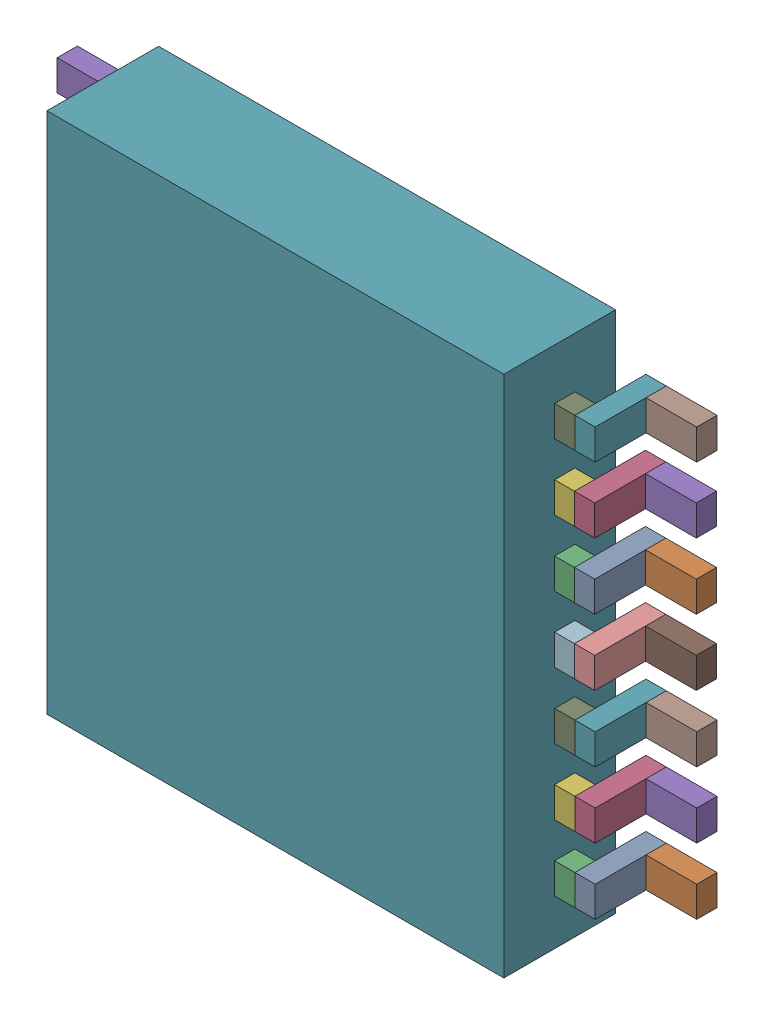
SolidWorks assembly U10, configuration Default. Lengths in mm.
Overall size (6.3 5.15 1.2).
86 component instances, 4 part files, 0 mates.
Components (placement in the parent):
- 836750064-1: 836750064 [Default] at (113.1 40.4 0) size (0.2 0.3 0.7)
  - Extruded_24-1: Extruded_24 [Default] at origin size (0.2 0.3 0.7)
- 836751344-1: 836751344 [Default] at (113.45 40.4 0) size (0.5 0.3 0.2)
  - Extruded_25-1: Extruded_25 [Default] at origin size (0.5 0.3 0.2)
- 836749808-1: 836749808 [Default] at (112.9 40.4 0.5) size (0.2 0.3 0.2)
  - Extruded_26-1: Extruded_26 [Default] at origin size (0.2 0.3 0.2)
- 836750064-2: 836750064 [Default] at (113.1 41.05 0) size (0.2 0.3 0.7)
  - Extruded_24-1: Extruded_24 [Default] at origin size (0.2 0.3 0.7)
- 836751344-2: 836751344 [Default] at (113.45 41.05 0) size (0.5 0.3 0.2)
  - Extruded_25-1: Extruded_25 [Default] at origin size (0.5 0.3 0.2)
- 836749808-2: 836749808 [Default] at (112.9 41.05 0.5) size (0.2 0.3 0.2)
  - Extruded_26-1: Extruded_26 [Default] at origin size (0.2 0.3 0.2)
- 836750064-3: 836750064 [Default] at (113.1 41.7 0) size (0.2 0.3 0.7)
  - Extruded_24-1: Extruded_24 [Default] at origin size (0.2 0.3 0.7)
- 836751344-3: 836751344 [Default] at (113.45 41.7 0) size (0.5 0.3 0.2)
  - Extruded_25-1: Extruded_25 [Default] at origin size (0.5 0.3 0.2)
- 836749808-3: 836749808 [Default] at (112.9 41.7 0.5) size (0.2 0.3 0.2)
  - Extruded_26-1: Extruded_26 [Default] at origin size (0.2 0.3 0.2)
- 836750064-4: 836750064 [Default] at (113.0954 42.35 0) size (0.2 0.3 0.7)
  - Extruded_24-1: Extruded_24 [Default] at origin size (0.2 0.3 0.7)
- 836751344-4: 836751344 [Default] at (113.4454 42.35 0) size (0.5 0.3 0.2)
  - Extruded_25-1: Extruded_25 [Default] at origin size (0.5 0.3 0.2)
- 836749808-4: 836749808 [Default] at (112.8954 42.35 0.5) size (0.2 0.3 0.2)
  - Extruded_26-1: Extruded_26 [Default] at origin size (0.2 0.3 0.2)
- 836750064-5: 836750064 [Default] at (113.0954 43 0) size (0.2 0.3 0.7)
  - Extruded_24-1: Extruded_24 [Default] at origin size (0.2 0.3 0.7)
- 836751344-5: 836751344 [Default] at (113.4454 43 0) size (0.5 0.3 0.2)
  - Extruded_25-1: Extruded_25 [Default] at origin size (0.5 0.3 0.2)
- 836749808-5: 836749808 [Default] at (112.8954 43 0.5) size (0.2 0.3 0.2)
  - Extruded_26-1: Extruded_26 [Default] at origin size (0.2 0.3 0.2)
- 836750064-6: 836750064 [Default] at (113.0954 43.65 0) size (0.2 0.3 0.7)
  - Extruded_24-1: Extruded_24 [Default] at origin size (0.2 0.3 0.7)
- 836751344-6: 836751344 [Default] at (113.4454 43.65 0) size (0.5 0.3 0.2)
  - Extruded_25-1: Extruded_25 [Default] at origin size (0.5 0.3 0.2)
- 836749808-6: 836749808 [Default] at (112.8954 43.65 0.5) size (0.2 0.3 0.2)
  - Extruded_26-1: Extruded_26 [Default] at origin size (0.2 0.3 0.2)
- 836750064-7: 836750064 [Default] at (113.1 44.3 0) size (0.2 0.3 0.7)
  - Extruded_24-1: Extruded_24 [Default] at origin size (0.2 0.3 0.7)
- 836751344-7: 836751344 [Default] at (113.45 44.3 0) size (0.5 0.3 0.2)
  - Extruded_25-1: Extruded_25 [Default] at origin size (0.5 0.3 0.2)
- 836749808-7: 836749808 [Default] at (112.9 44.3 0.5) size (0.2 0.3 0.2)
  - Extruded_26-1: Extruded_26 [Default] at origin size (0.2 0.3 0.2)
- 836750064-8: 836750064 [Default] at (108 40.4 0) size (0.2 0.3 0.7)
  - Extruded_24-1: Extruded_24 [Default] at origin size (0.2 0.3 0.7)
- 836751344-8: 836751344 [Default] at (107.65 40.4 0) size (0.5 0.3 0.2)
  - Extruded_25-1: Extruded_25 [Default] at origin size (0.5 0.3 0.2)
- 836749808-8: 836749808 [Default] at (108.2 40.4 0.5) size (0.2 0.3 0.2)
  - Extruded_26-1: Extruded_26 [Default] at origin size (0.2 0.3 0.2)
- 836750064-9: 836750064 [Default] at (108 41.05 0) size (0.2 0.3 0.7)
  - Extruded_24-1: Extruded_24 [Default] at origin size (0.2 0.3 0.7)
- 836751344-9: 836751344 [Default] at (107.65 41.05 0) size (0.5 0.3 0.2)
  - Extruded_25-1: Extruded_25 [Default] at origin size (0.5 0.3 0.2)
- 836749808-9: 836749808 [Default] at (108.2 41.05 0.5) size (0.2 0.3 0.2)
  - Extruded_26-1: Extruded_26 [Default] at origin size (0.2 0.3 0.2)
- 836750064-10: 836750064 [Default] at (108 41.7 0) size (0.2 0.3 0.7)
  - Extruded_24-1: Extruded_24 [Default] at origin size (0.2 0.3 0.7)
- 836751344-10: 836751344 [Default] at (107.65 41.7 0) size (0.5 0.3 0.2)
  - Extruded_25-1: Extruded_25 [Default] at origin size (0.5 0.3 0.2)
- 836749808-10: 836749808 [Default] at (108.2 41.7 0.5) size (0.2 0.3 0.2)
  - Extruded_26-1: Extruded_26 [Default] at origin size (0.2 0.3 0.2)
- 836750064-11: 836750064 [Default] at (108 42.35 0) size (0.2 0.3 0.7)
  - Extruded_24-1: Extruded_24 [Default] at origin size (0.2 0.3 0.7)
- 836751344-11: 836751344 [Default] at (107.65 42.35 0) size (0.5 0.3 0.2)
  - Extruded_25-1: Extruded_25 [Default] at origin size (0.5 0.3 0.2)
- 836749808-11: 836749808 [Default] at (108.2 42.35 0.5) size (0.2 0.3 0.2)
  - Extruded_26-1: Extruded_26 [Default] at origin size (0.2 0.3 0.2)
- 836750064-12: 836750064 [Default] at (108 43 0) size (0.2 0.3 0.7)
  - Extruded_24-1: Extruded_24 [Default] at origin size (0.2 0.3 0.7)
- 836751344-12: 836751344 [Default] at (107.65 43 0) size (0.5 0.3 0.2)
  - Extruded_25-1: Extruded_25 [Default] at origin size (0.5 0.3 0.2)
- 836749808-12: 836749808 [Default] at (108.2 43 0.5) size (0.2 0.3 0.2)
  - Extruded_26-1: Extruded_26 [Default] at origin size (0.2 0.3 0.2)
- 836750064-13: 836750064 [Default] at (108 43.65 0) size (0.2 0.3 0.7)
  - Extruded_24-1: Extruded_24 [Default] at origin size (0.2 0.3 0.7)
- 836751344-13: 836751344 [Default] at (107.65 43.65 0) size (0.5 0.3 0.2)
  - Extruded_25-1: Extruded_25 [Default] at origin size (0.5 0.3 0.2)
- 836749808-13: 836749808 [Default] at (108.2 43.65 0.5) size (0.2 0.3 0.2)
  - Extruded_26-1: Extruded_26 [Default] at origin size (0.2 0.3 0.2)
- 836749808-14: 836749808 [Default] at (108.2 44.3 0.5) size (0.2 0.3 0.2)
  - Extruded_26-1: Extruded_26 [Default] at origin size (0.2 0.3 0.2)
- 836751344-14: 836751344 [Default] at (107.65 44.3 0) size (0.5 0.3 0.2)
  - Extruded_25-1: Extruded_25 [Default] at origin size (0.5 0.3 0.2)
- 836750064-14: 836750064 [Default] at (108 44.3 0) size (0.2 0.3 0.7)
  - Extruded_24-1: Extruded_24 [Default] at origin size (0.2 0.3 0.7)
- 859196720-1: 859196720 [Default] at (110.55 42.375 0.1) size (4.5 5.15 1.1)
  - Extruded_27-1: Extruded_27 [Default] at origin size (4.5 5.15 1.1)
